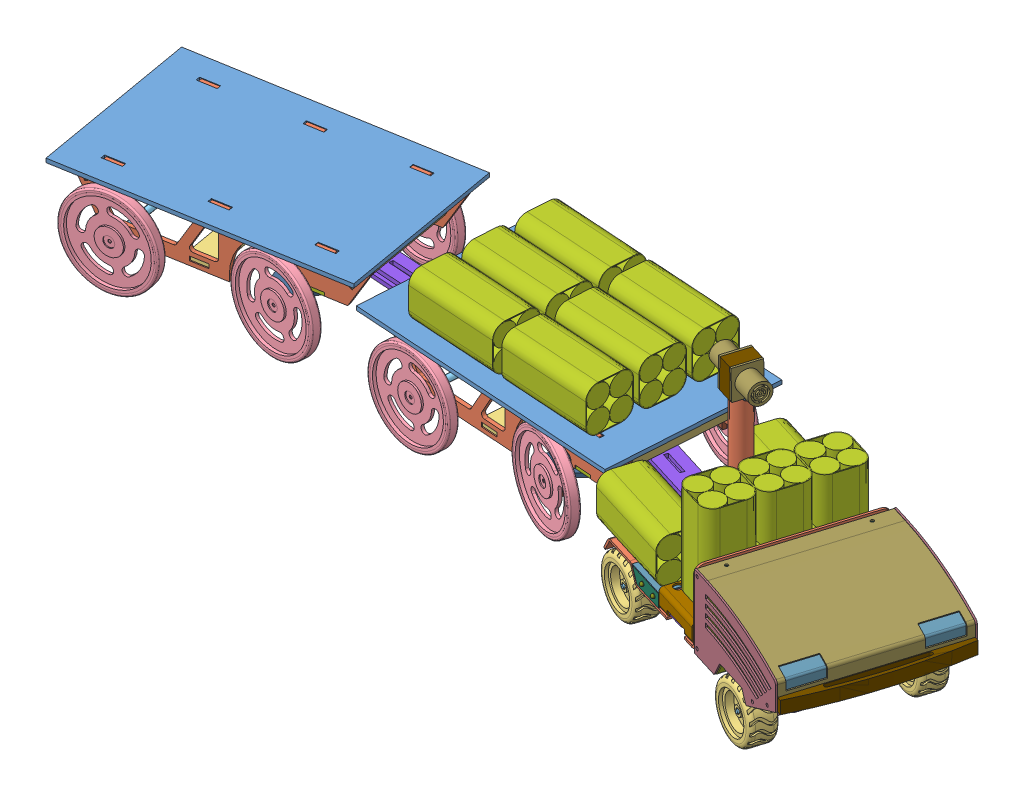
SolidWorks assembly TEST, WAGON ASSEMBLY, configuration Default. Lengths in mm.
Overall size (695.65 182.17 246.56).
138 component instances, 49 part files, 6 mates.
Components (placement in the parent):
- Battery Fit Test-1: Battery Fit Test [Default] at (203.1295 138.389 50.8779) x (0.295221 -0.000435 -0.955429) z (0.955428 -0.001409 0.295221) size (124.43 170.93 223.86)
  - SCOUT, TOP LEVEL-1: SCOUT, TOP LEVEL [Default] at (-3.115 -49.4333 19.8217) size (124.43 170.93 223.86)
    - 6655k13 Thrust Washers-1: 6655k13 Thrust Washers [Default] at (-7.8856 2.7539 2.2902) size (14.15 14.15 4.9)
    - REAR, TOP LEVEL-1: REAR, TOP LEVEL [Default] at (-50.0168 -33.3245 -47.0081) x (-1 0 0) z (0 0 -1) size (124.43 170.93 120.66)
      - PLATE, REAR-1: PLATE, REAR [Default] at (-42.1312 28.0774 12.7174) size (120.65 55.63 120.66)
      - WHEEL ASSEMBLY-1: WHEEL ASSEMBLY [Default-_flexible1] at (7.6153 26.9792 58.7651) x (0 0 1) z (1 0 0) size (42.46 78.6 70.03) (flexible)
        - Pololu 49x19 Wheel-1: Pololu 49x19 Wheel [Default] at (-19.8703 11.8393 2.4418) size (42.46 42.56 19)
        - Pololu Extended Micro Metal Bracket-1: Pololu Extended Micro Metal Bracket [Default] at (-19.8703 6.8393 -18.4366) size (26.6 22.49 26.04)
        - Pololu 298-1 Motor-1: Pololu 298-1 Motor [Default] at (-19.8703 11.8393 -25.1366) x (0 0 -1) z (0 1 0) size (35.87 12 10)
      - WHEEL ASSEMBLY-2: WHEEL ASSEMBLY [Default-_flexible2] at (-91.8778 26.9792 19.0244) x (0 0 -1) z (-1 0 0) size (42.46 78.6 70.03) (flexible)
        - Pololu 49x19 Wheel-1: Pololu 49x19 Wheel [Default] at (-19.8703 11.8393 2.4418) size (42.46 42.56 19)
        - Pololu Extended Micro Metal Bracket-1: Pololu Extended Micro Metal Bracket [Default] at (-19.8703 6.8393 -18.4366) size (26.6 22.49 26.04)
        - Pololu 298-1 Motor-1: Pololu 298-1 Motor [Default] at (-19.8703 11.8393 -25.1366) x (0 0 -1) z (0 1 0) size (35.87 12 10)
      - Socket Head Cap Screw_AI-9: Socket Head Cap Screw_AI [HX-SHCS 0.086-56x0.4375x0.4375-N] at (-77.6912 31.9128 47.8948) x (0 -1 0) z (-0.381305 0 -0.924449) size (13.3 3.56 3.56)
      - Socket Head Cap Screw_AI-10: Socket Head Cap Screw_AI [HX-SHCS 0.086-56x0.4375x0.4375-N] at (-77.6912 31.9128 29.8948) x (0 -1 0) z (0 0 1) size (13.3 3.56 3.56)
      - Socket Head Cap Screw_AI-11: Socket Head Cap Screw_AI [HX-SHCS 0.086-56x0.4375x0.4375-N] at (-6.5712 31.9128 29.8948) x (0 -1 0) z (0 0 1) size (13.3 3.56 3.56)
      - Socket Head Cap Screw_AI-12: Socket Head Cap Screw_AI [HX-SHCS 0.086-56x0.4375x0.4375-N] at (-6.5712 31.9128 47.8948) x (0 -1 0) z (0 0 1) size (13.3 3.56 3.56)
      - 4000mAh 7.4V Battery Pack-1: 4000mAh 7.4V Battery Pack [Default] at (-42.1312 61.2244 -25.3842) x (0 0 -1) z (1 0 0) size (34.29 34.29 68.58)
      - SENSOR, GP2Y0D810-1: SENSOR, GP2Y0D810 [Default] at (9.9271 36.6454 -23.9419) x (0 0 -1) z (0.766044 0.642788 0) size (28.32 10.54 8.89)
      - SENSOR, GP2Y0D810-2: SENSOR, GP2Y0D810 [Default] at (-94.1896 36.6454 -23.9419) x (0 0 -1) z (0.766044 -0.642788 0) size (28.32 10.54 8.89)
      - Battery Support-1: Battery Support [Default] at (-42.1312 29.7284 -26.0192) size (120.65 27.05 38.1)
      - Mounting Block-1: Mounting Block [Default] at (-42.1312 36.0784 -35.6712) x (-1 0 0) z (0 0 -1) size (25.4 12.7 25.4)
      - PF35T-48-1: PF35T-48 [Default] at (-42.1312 31.7284 12.5888) x (-1 0 0) z (0 0 -1) size (50 29.2 35)
      - MaxSonar EZ1-1: MaxSonar EZ1 [Default] at (-42.1312 153.1691 6.6293) x (-1 0 0) z (0 0.034899 -0.999391) size (19.94 22.1 16.38)
      - MaxSonar EZ1-2: MaxSonar EZ1 [Default] at (-42.1312 153.1691 18.5483) x (1 0 0) z (0 0.034899 0.999391) size (19.94 22.1 16.38)
      - BUMPER, REAR-1: BUMPER, REAR [Default] at (-42.1312 29.7284 53.2288) x (-1 0 0) z (0 0 -1) size (80.01 9.53 54.3)
      - PLATE, REAR COVER-1: PLATE, REAR COVER [Default] at (-42.1312 39.2534 72.2788) size (120.65 0.81 81.14)
      - MOUNTING BLOCK, COLOR SENSOR-1: MOUNTING BLOCK, COLOR SENSOR [Default] at (-97.6937 29.7284 5.6038) size (9.53 9.53 30.46)
      - MOUNTING BLOCK, COLOR SENSOR-2: MOUNTING BLOCK, COLOR SENSOR [Default] at (13.4313 29.7284 5.6038) size (9.53 9.53 30.46)
      - SENSOR, COLOR LED-1: SENSOR, COLOR LED [Default] at (-24.0807 23.782 31.9371) x (0 0 -1) z (-0.409692 -0.912224 0) size (5.83 3.66 3.66)
      - SENSOR, COLOR LED-2: SENSOR, COLOR LED [Default] at (-67.3741 22.996 31.9371) x (0 0 -1) z (-0.202984 -0.979182 0) size (5.83 3.66 3.66)
      - COPPER CONTACT-1: COPPER CONTACT [Default] at (-53.2437 34.4909 64.0238) size (15.88 6.35 4.45)
      - COPPER CONTACT-2: COPPER CONTACT [Default] at (-31.0187 34.4909 64.0238) size (15.88 6.35 4.45)
      - MOUNTING BLOCK, SONAR-1: MOUNTING BLOCK, SONAR [Default] at (-42.1312 153.0989 12.5888) x (-1 0 0) z (0 0 -1) size (19.94 22.23 12.7)
      - SHAFT, SONAR MOUNT-1: SHAFT, SONAR MOUNT [Default] at (-42.1312 52.5784 12.5888) x (-0.538443 0 0.842662) z (-0.842662 0 -0.538443) size (4.76 102.11 4.76)
      - SHAFT, SONAR SUPPORT-1: SHAFT, SONAR SUPPORT [Default] at (-42.1312 46.7284 12.5888) x (0.999987 0 0.005105) z (-0.005105 0 0.999987) size (14.22 95.57 14.22)
      - SHAFT, STEPPER SUPPORT-1: SHAFT, STEPPER SUPPORT [Default] at (-63.1312 29.6724 12.5888) size (4.76 16.26 4.76)
      - SHAFT, STEPPER SUPPORT-2: SHAFT, STEPPER SUPPORT [Default] at (-21.1312 29.6724 12.5888) x (0.987866 0 -0.155311) z (0.155311 0 0.987866) size (4.76 16.26 4.76)
      - Flat Head 100 Screw_AI-6: Flat Head 100 Screw_AI [CR-FHM1 0.112-40x0.25x0.25-N] at (-63.1312 46.7284 12.5888) x (0 -1 0) z (0 0 1) size (6.35 4.85 4.85)
      - Flat Head 100 Screw_AI-7: Flat Head 100 Screw_AI [CR-FHM1 0.112-40x0.25x0.25-N] at (-21.1312 46.7284 12.5888) x (0 -1 0) z (0 0 1) size (6.35 4.85 4.85)
      - CONNECTOR, MOLEX 6 PIN-1: CONNECTOR, MOLEX 6 PIN [Default] at (-80.2263 37.7912 12.5433) size (10.34 13.8 9.75)
      - SENSOR, COLOR LED-3: SENSOR, COLOR LED [Default] at (-64.0196 42.7147 3.5765) x (1 0 0) z (0 0.700538 -0.713616) size (5.83 3.66 3.66)
      - SENSOR, COLOR LED-4: SENSOR, COLOR LED [Default] at (-64.0196 42.7147 -9.1235) x (1 0 0) z (0 0.700538 -0.713616) size (5.83 3.66 3.66)
      - SENSOR, COLOR LED-5: SENSOR, COLOR LED [Default] at (-20.2429 42.7147 20.3311) x (-1 0 0) z (0 0.700538 0.713616) size (5.83 3.66 3.66)
      - SENSOR, COLOR LED-6: SENSOR, COLOR LED [Default] at (-20.2429 42.7147 7.6311) x (-1 0 0) z (0 0.700538 0.713616) size (5.83 3.66 3.66)
      - MOUNTING BLOCK, REAR-1: MOUNTING BLOCK, REAR [Default] at (-58.0062 34.4909 31.0038) size (9.53 9.53 28.57)
      - MOUNTING BLOCK, REAR-2: MOUNTING BLOCK, REAR [Default] at (-26.2562 34.4909 31.0038) size (9.53 9.53 28.57)
      - SW3dPS-Sliderswitch-1: SW3dPS-Sliderswitch [Standard] at (-81.1109 44.0794 -21.7288) (suppressed, hidden)
    - FRONT, TOP LEVEL-1: FRONT, TOP LEVEL [Default] at (-84.349 -51.7544 28.3431) x (-1 0 0) z (0 0 -1) size (123.38 89.85 131.19)
      - PLATE, FRONT-1: PLATE, FRONT [Default] at (-76.4634 46.5072 -32.0242) size (120.65 12.1 60.8)
      - WHEEL ASSEMBLY-1: WHEEL ASSEMBLY [Default-_flexible3] at (-26.7168 45.4091 2.1802) x (0 0 1) z (1 0 0) size (42.46 78.6 70.03) (flexible)
        - Pololu 49x19 Wheel-1: Pololu 49x19 Wheel [Default] at (-19.8703 11.8393 2.4418) size (42.46 42.56 19)
        - Pololu Extended Micro Metal Bracket-1: Pololu Extended Micro Metal Bracket [Default] at (-19.8703 6.8393 -18.4366) size (26.6 22.49 26.04)
        - Pololu 298-1 Motor-1: Pololu 298-1 Motor [Default] at (-19.8703 11.8393 -25.1366) x (0 0 -1) z (0 1 0) size (35.87 12 10)
      - WHEEL ASSEMBLY-2: WHEEL ASSEMBLY [Default-_flexible4] at (-126.21 45.4091 -37.5605) x (0 0 -1) z (-1 0 0) size (42.46 78.6 70.03) (flexible)
        - Pololu 49x19 Wheel-1: Pololu 49x19 Wheel [Default] at (-19.8703 11.8393 2.4418) size (42.46 42.56 19)
        - Pololu Extended Micro Metal Bracket-1: Pololu Extended Micro Metal Bracket [Default] at (-19.8703 6.8393 -18.4366) size (26.6 22.49 26.04)
        - Pololu 298-1 Motor-1: Pololu 298-1 Motor [Default] at (-19.8703 11.8393 -25.1366) x (0 0 -1) z (0 1 0) size (35.87 12 10)
      - Socket Head Cap Screw_AI-11: Socket Head Cap Screw_AI [HX-SHCS 0.086-56x0.4375x0.4375-N] at (-112.0234 50.3426 -8.6902) x (0 -1 0) z (0.989468 0 0.144748) size (13.3 3.56 3.56)
      - Socket Head Cap Screw_AI-12: Socket Head Cap Screw_AI [HX-SHCS 0.086-56x0.4375x0.4375-N] at (-40.9034 50.3426 -8.6902) x (0 -1 0) z (0.700957 0 0.713204) size (13.3 3.56 3.56)
      - SENSOR, GP2Y0D810-2: SENSOR, GP2Y0D810 [Default] at (-76.7491 52.0249 -21.9932) x (1 0 0) z (0 -0.642788 0.766044) size (28.32 10.54 8.89)
      - BUMPER, FRONT-1: BUMPER, FRONT [Default] at (-76.4634 36.9822 -30.9902) x (-1 0 0) z (0 0 -1) size (69.85 9.53 6.35)
      - Mounting Block-1: Mounting Block [Default] at (-76.4634 54.5082 12.4258) size (25.4 12.7 25.4)
      - Socket Head Shoulder Screw2_AI-2: Socket Head Shoulder Screw2_AI [SHSSCREW 0.25x1.5-N] at (-76.4634 54.5082 2.5706) x (0 0 1) z (-0.728467 -0.685081 0) size (52.4 9.53 9.53)
      - Socket Head Cap Screw_AI-13: Socket Head Cap Screw_AI [HX-SHCS 0.086-56x0.4375x0.4375-N] at (-40.9034 51.2773 -26.6902) x (0 -1 0) z (-0.957829 0 -0.287339) size (13.3 3.56 3.56)
      - Socket Head Cap Screw_AI-14: Socket Head Cap Screw_AI [HX-SHCS 0.086-56x0.4375x0.4375-N] at (-112.0234 51.2773 -26.6902) x (0 -1 0) z (-0.957829 0 -0.287339) size (13.3 3.56 3.56)
      - PCB, MAIN-1: PCB, MAIN [Default] at (-76.4634 67.2082 -21.6044) size (114.3 6.68 88.9)
      - PLATE, FRONT BUMPER-1: PLATE, FRONT BUMPER [Default] at (-76.4634 48.9202 -22.7941) size (120.65 17.91 44.79)
      - COVER, FRONT-1: COVER, FRONT [Default] at (-76.4634 65.9445 25.1258) size (120.65 35.94 93.73)
      - PLATE, FRONT SIDE-1: PLATE, FRONT SIDE [Default] at (-16.1384 46.5072 25.1258) x (0 0 -1) z (1 0 0) size (93.73 55.63 1.27)
      - SW3dPS-USB_mini_B-1: SW3dPS-USB_mini_B [По умолчанию] at (-54.9865 68.8084 -58.5669) x (-1 0 0) z (0 0 -1) (suppressed, hidden)
      - HEADLIGHT COVER, FRONT-1: HEADLIGHT COVER, FRONT [Default] at (-103.1334 74.8345 -67.5842) x (-1 0 0) z (0 0 -1) size (31.75 14.4 11.68)
      - HEADLIGHT COVER, FRONT-2: HEADLIGHT COVER, FRONT [Default] at (-18.0434 74.8345 -67.5842) x (-1 0 0) z (0 0 -1) size (31.75 14.4 11.68)
      - PLATE, FRONT SIDE-2: PLATE, FRONT SIDE [Default] at (-138.0584 46.5072 25.1258) x (0 0 -1) z (1 0 0) size (93.73 55.63 1.27)
      - STRUT, FRONT SIDE-1: STRUT, FRONT SIDE [Default] at (-76.4634 98.9582 21.9508) size (120.65 3.17 6.35)
      - FILTER, FRONT COVER-1: FILTER, FRONT COVER [Default] at (-19.1356 62.8553 14.5951) x (0 0 -1) z (1 0 0) size (76.17 31.33 3)
      - FILTER, FRONT COVER-2: FILTER, FRONT COVER [Default] at (-136.7884 62.8559 13.2551) x (0 0 -1) z (1 0 0) size (76.17 31.33 3)
      - Orb LED-1: Orb LED [Default] at (-118.9744 68.8084 -63.3886) size (6.35 9.53 6.35)
      - Orb LED-2: Orb LED [Default] at (-34.5831 68.8084 -63.3886) size (6.35 9.53 6.35)
      - BUMPER, FRONT SWITCHED-1: BUMPER, FRONT SWITCHED [Default] at (-76.4634 70.707 -70.1877) x (-1 0 0) z (0 0 -1) size (120.65 9.53 7.62)
    - BUMPER, FRONT SWITCHED-1: BUMPER, FRONT SWITCHED [Default] at (-7.8856 18.9527 98.5308) size (120.65 9.53 7.62)
  - 4000mAh 7.4V Battery Pack-3: 4000mAh 7.4V Battery Pack [Default] at (24.0035 -4.3884 -1.8023) x (1 0 0) z (0 -1 0) size (34.29 34.29 68.58)
  - 4000mAh 7.4V Battery Pack-4: 4000mAh 7.4V Battery Pack [Default] at (-10.2865 -4.3884 -1.8023) x (1 0 0) z (0 -1 0) size (34.29 34.29 68.58)
  - 4000mAh 7.4V Battery Pack-5: 4000mAh 7.4V Battery Pack [Default] at (-44.5765 -4.3884 -1.8023) x (1 0 0) z (0 -1 0) size (34.29 34.29 68.58)
  - 4000mAh 7.4V Battery Pack-6: 4000mAh 7.4V Battery Pack [Default] at (-54.5068 -25.5466 -57.6477) x (1 0 0) z (0 0 -1) size (34.29 34.29 68.58)
  - 4000mAh 7.4V Battery Pack-7: 4000mAh 7.4V Battery Pack [Default] at (29.5929 -25.5466 -57.6477) x (1 0 0) z (0 0 -1) size (34.29 34.29 68.58)
  - 4000mAh 7.4V Battery Pack-8: 4000mAh 7.4V Battery Pack [Default] at (-54.5068 8.7434 -57.6477) x (1 0 0) z (0 0 -1) size (34.29 34.29 68.58) (suppressed, hidden)
  - 4000mAh 7.4V Battery Pack-9: 4000mAh 7.4V Battery Pack [Default] at (29.5929 8.7434 -57.6477) x (1 0 0) z (0 0 -1) size (34.29 34.29 68.58) (suppressed, hidden)
- TOP LEVEL, WAGON-3: TOP LEVEL, WAGON [Default] at (92.0678 103.8329 -16.9806) x (0.997941 -0.001472 0.064123) z (-0.064123 0.000095 0.997942) size (258.54 94.79 146.21)
  - PLATE, TOP-1: PLATE, TOP [Default] at (-95.5068 20.3037 36.6036) size (203.2 3 127)
  - PLATE, SIDE PANEL-1: PLATE, SIDE PANEL [Default] at (-95.5068 -1.9213 79.6439) size (203.2 46.99 3)
  - PLATE, SIDE PANEL-2: PLATE, SIDE PANEL [Default] at (-95.5068 -1.9213 -9.4339) size (203.2 46.99 3)
  - STRUT, SIDE PANEL-1: STRUT, SIDE PANEL [Default] at (-108.2068 -20.7935 36.6036) size (19.05 3 90.8)
  - STRUT, SIDE PANEL-2: STRUT, SIDE PANEL [Default] at (-186.8929 9.1913 36.6036) x (0.5 -0.866025 0) z (0 0 1) size (19.05 3 90.8)
  - STRUT, SIDE PANEL-3: STRUT, SIDE PANEL [Default] at (-4.0766 9.1659 36.6036) x (0.5 0.866025 0) z (0 0 1) size (19.05 3 90.8)
  - gm8_wheel-4: gm8_wheel [Default] at (-159.0068 -19.3838 -19.5685) x (0 0 -1) z (0.524321 0.851521 0) size (7.52 66.8 66.8)
  - SHAFT-4: SHAFT [Default] at (-159.0068 -19.3838 36.6036) x (-0.36459 0.931168 0) z (0 0 1) size (4.76 4.76 101.6)
  - ARM, LINKING-3: ARM, LINKING [Default] at (-44.3561 -3.9152 1.8901) x (0.972393 0 0.233349) z (-0.233349 0 0.972393) size (34.92 3 9.53)
  - ARM, LINKING-4: ARM, LINKING [Default] at (-44.3561 -3.9152 65.3901) x (0.972393 0 0.233349) z (-0.233349 0 0.972393) size (34.92 3 9.53)
  - STRUT, RIGID CROSSBAR-1: STRUT, RIGID CROSSBAR [Default] at (-32.0068 -8.411 36.6036) size (19.05 3 90.8)
  - ARM, STEERING-2: ARM, STEERING [Default] at (-7.308 -5.4138 42.5307) x (0.972393 0 0.233349) z (-0.233349 0 0.972393) size (120.65 3 19.05)
  - ARM, STEERING CROSSBAR-4: ARM, STEERING CROSSBAR [Default] at (-56.7055 -6.9124 30.6765) x (0 0 1) z (-1 0 0) size (76.2 3 12.7)
  - MOUNT, WHEEL-3: MOUNT, WHEEL [Default] at (-44.3561 -9.9096 1.8901) x (-0.233349 0 0.972393) z (-0.972393 0 -0.233349) size (28.57 3 38.1)
  - MOUNT, WHEEL-4: MOUNT, WHEEL [Default] at (-44.3561 -9.9096 65.3901) x (0.233349 0 -0.972393) z (0.972393 0 0.233349) size (28.57 3 38.1)
  - gm8_wheel-5: gm8_wheel [Default] at (-159.0068 -19.3838 92.7757) x (0 0 1) z (-0.273028 0.962006 0) size (7.52 66.8 66.8)
  - ARM, STEERING-4: ARM, STEERING [Default] at (-7.308 -11.4082 42.5307) x (0.972393 0 0.233349) z (-0.233349 0 0.972393) size (120.65 3 19.05)
  - MOUNT, WHEEL PIVOT-1: MOUNT, WHEEL PIVOT [Default] at (-49.5631 -17.7582 87.088) x (0.972393 0 0.233349) z (-0.233349 0 0.972393) size (19.05 12.7 3)
  - MOUNT, WHEEL PIVOT-2: MOUNT, WHEEL PIVOT [Default] at (-39.1492 -17.7582 -19.8078) x (0.972393 0 0.233349) z (-0.233349 0 0.972393) size (19.05 12.7 3)
  - gm8_wheel-6: gm8_wheel [Default] at (-50.7959 -17.7582 92.2253) x (-0.233349 0 0.972393) z (-0.523066 0.842998 -0.125522) size (7.52 66.8 66.8)
  - gm8_wheel-7: gm8_wheel [Default] at (-37.9164 -17.7582 -24.9452) x (0.233349 0 -0.972393) z (0.662777 0.73173 0.159049) size (7.52 66.8 66.8)
- TOP LEVEL, WAGON-4: TOP LEVEL, WAGON [Default] at (-149.6327 104.1893 -40.8644) x (0.985354 -0.001453 -0.170517) z (0.170516 -0.000251 0.985355) size (258.54 94.79 146.21)
  - PLATE, TOP-1: PLATE, TOP [Default] at (-95.5068 20.3037 36.6036) size (203.2 3 127)
  - PLATE, SIDE PANEL-1: PLATE, SIDE PANEL [Default] at (-95.5068 -1.9213 79.6439) size (203.2 46.99 3)
  - PLATE, SIDE PANEL-2: PLATE, SIDE PANEL [Default] at (-95.5068 -1.9213 -9.4339) size (203.2 46.99 3)
  - STRUT, SIDE PANEL-1: STRUT, SIDE PANEL [Default] at (-108.2068 -20.7935 36.6036) size (19.05 3 90.8)
  - STRUT, SIDE PANEL-2: STRUT, SIDE PANEL [Default] at (-186.8929 9.1913 36.6036) x (0.5 -0.866025 0) z (0 0 1) size (19.05 3 90.8)
  - STRUT, SIDE PANEL-3: STRUT, SIDE PANEL [Default] at (-4.0766 9.1659 36.6036) x (0.5 0.866025 0) z (0 0 1) size (19.05 3 90.8)
  - gm8_wheel-4: gm8_wheel [Default] at (-159.0068 -19.3838 -19.5685) x (0 0 -1) z (0.524321 0.851521 0) size (7.52 66.8 66.8)
  - SHAFT-4: SHAFT [Default] at (-159.0068 -19.3838 36.6036) x (-0.36459 0.931168 0) z (0 0 1) size (4.76 4.76 101.6)
  - ARM, LINKING-3: ARM, LINKING [Default] at (-44.3561 -3.9152 1.8901) x (0.972393 0 0.233349) z (-0.233349 0 0.972393) size (34.92 3 9.53)
  - ARM, LINKING-4: ARM, LINKING [Default] at (-44.3561 -3.9152 65.3901) x (0.972393 0 0.233349) z (-0.233349 0 0.972393) size (34.92 3 9.53)
  - STRUT, RIGID CROSSBAR-1: STRUT, RIGID CROSSBAR [Default] at (-32.0068 -8.411 36.6036) size (19.05 3 90.8)
  - ARM, STEERING-2: ARM, STEERING [Default] at (-7.308 -5.4138 42.5307) x (0.972393 0 0.233349) z (-0.233349 0 0.972393) size (120.65 3 19.05)
  - ARM, STEERING CROSSBAR-4: ARM, STEERING CROSSBAR [Default] at (-56.7055 -6.9124 30.6765) x (0 0 1) z (-1 0 0) size (76.2 3 12.7)
  - MOUNT, WHEEL-3: MOUNT, WHEEL [Default] at (-44.3561 -9.9096 1.8901) x (-0.233349 0 0.972393) z (-0.972393 0 -0.233349) size (28.57 3 38.1)
  - MOUNT, WHEEL-4: MOUNT, WHEEL [Default] at (-44.3561 -9.9096 65.3901) x (0.233349 0 -0.972393) z (0.972393 0 0.233349) size (28.57 3 38.1)
  - gm8_wheel-5: gm8_wheel [Default] at (-159.0068 -19.3838 92.7757) x (0 0 1) z (-0.273028 0.962006 0) size (7.52 66.8 66.8)
  - ARM, STEERING-4: ARM, STEERING [Default] at (-7.308 -11.4082 42.5307) x (0.972393 0 0.233349) z (-0.233349 0 0.972393) size (120.65 3 19.05)
  - MOUNT, WHEEL PIVOT-1: MOUNT, WHEEL PIVOT [Default] at (-49.5631 -17.7582 87.088) x (0.972393 0 0.233349) z (-0.233349 0 0.972393) size (19.05 12.7 3)
  - MOUNT, WHEEL PIVOT-2: MOUNT, WHEEL PIVOT [Default] at (-39.1492 -17.7582 -19.8078) x (0.972393 0 0.233349) z (-0.233349 0 0.972393) size (19.05 12.7 3)
  - gm8_wheel-6: gm8_wheel [Default] at (-50.7959 -17.7582 92.2253) x (-0.233349 0 0.972393) z (-0.523066 0.842998 -0.125522) size (7.52 66.8 66.8)
  - gm8_wheel-7: gm8_wheel [Default] at (-37.9164 -17.7582 -24.9452) x (0.233349 0 -0.972393) z (0.662777 0.73173 0.159049) size (7.52 66.8 66.8)
- 4000mAh 7.4V Battery Pack-1: 4000mAh 7.4V Battery Pack [Default] at (36.9667 144.3601 -23.9333) x (0.064123 -0.000095 -0.997942) z (-0.997941 0.001472 -0.064123) size (34.29 34.29 68.58)
- 4000mAh 7.4V Battery Pack-4: 4000mAh 7.4V Battery Pack [Default] at (-39.0764 144.4722 -28.8195) x (0.064123 -0.000095 -0.997942) z (-0.997941 0.001472 -0.064123) size (34.29 34.29 68.58)
- 4000mAh 7.4V Battery Pack-5: 4000mAh 7.4V Battery Pack [Default] at (34.5236 144.3637 14.0883) x (0.064123 -0.000095 -0.997942) z (-0.997941 0.001472 -0.064123) size (34.29 34.29 68.58)
- 4000mAh 7.4V Battery Pack-6: 4000mAh 7.4V Battery Pack [Default] at (-41.5195 144.4758 9.2021) x (0.064123 -0.000095 -0.997942) z (-0.997941 0.001472 -0.064123) size (34.29 34.29 68.58)
- 4000mAh 7.4V Battery Pack-7: 4000mAh 7.4V Battery Pack [Default] at (32.0806 144.3673 52.1099) x (0.064123 -0.000095 -0.997942) z (-0.997941 0.001472 -0.064123) size (34.29 34.29 68.58)
- 4000mAh 7.4V Battery Pack-8: 4000mAh 7.4V Battery Pack [Default] at (-43.9625 144.4794 47.2237) x (0.064123 -0.000095 -0.997942) z (-0.997941 0.001472 -0.064123) size (34.29 34.29 68.58)
Mates (geometry in assembly coordinates):
- Parallel3: parallel aligned: plane of Battery Fit Test-1/SCOUT, TOP LEVEL-1/REAR, TOP LEVEL-1/WHEEL ASSEMBLY-1/Pololu 49x19 Wheel-1 through (120.7964 70.8924 93.175) normal (-0.295221 0.000435 0.955429); plane of TOP LEVEL, WAGON-3/gm8_wheel-6 through (-3.5798 95.1635 60.9209) normal (-0.295221 0.000435 0.955429)
- Concentric8: concentric aligned: cylinder of Battery Fit Test-1/SCOUT, TOP LEVEL-1/REAR, TOP LEVEL-1/PLATE, REAR COVER-1 through (130.5705 94.9915 39.9912) axis (0.001475 0.999999 0) radius 3.2385; cylinder of TOP LEVEL, WAGON-3/ARM, STEERING-2 through (130.5755 98.3623 39.9912) axis (0.001475 0.999999 0) radius 3.175
- Parallel4: parallel aligned: plane of TOP LEVEL, WAGON-3/gm8_wheel-5 through (-108.7798 104.9524 64.2136) normal (-0.064123 0.000095 0.997942); plane of TOP LEVEL, WAGON-4/gm8_wheel-6 through (-224.4618 95.4892 57.2028) normal (-0.064123 0.000095 0.997942)
- Coincident1: coincident aligned: plane of TOP LEVEL, WAGON-3/PLATE, TOP-1 through (99.9075 127.1222 -43.4309) normal (0.001475 0.999999 0); plane of TOP LEVEL, WAGON-4/PLATE, TOP-1 through (-148.1806 127.4881 -68.4059) normal (0.001475 0.999999 0)
- Coincident2: coincident anti-aligned: plane of TOP LEVEL, WAGON-3/PLATE, TOP-1 through (99.9075 127.1222 -43.4309) normal (0.001475 0.999999 0); plane of 4000mAh 7.4V Battery Pack-1 through (71.6901 127.1639 -29.9726) normal (-0.001475 -0.999999 0)
- Distance1: distance = 6.35 mm aligned: plane of TOP LEVEL, WAGON-3/PLATE, TOP-1 through (-102.8741 127.4213 -56.4606) normal (0.064123 -0.000095 -0.997942); plane of 4000mAh 7.4V Battery Pack-1 through (72.2977 152.563 -38.8443) normal (0.064123 -0.000095 -0.997942)
